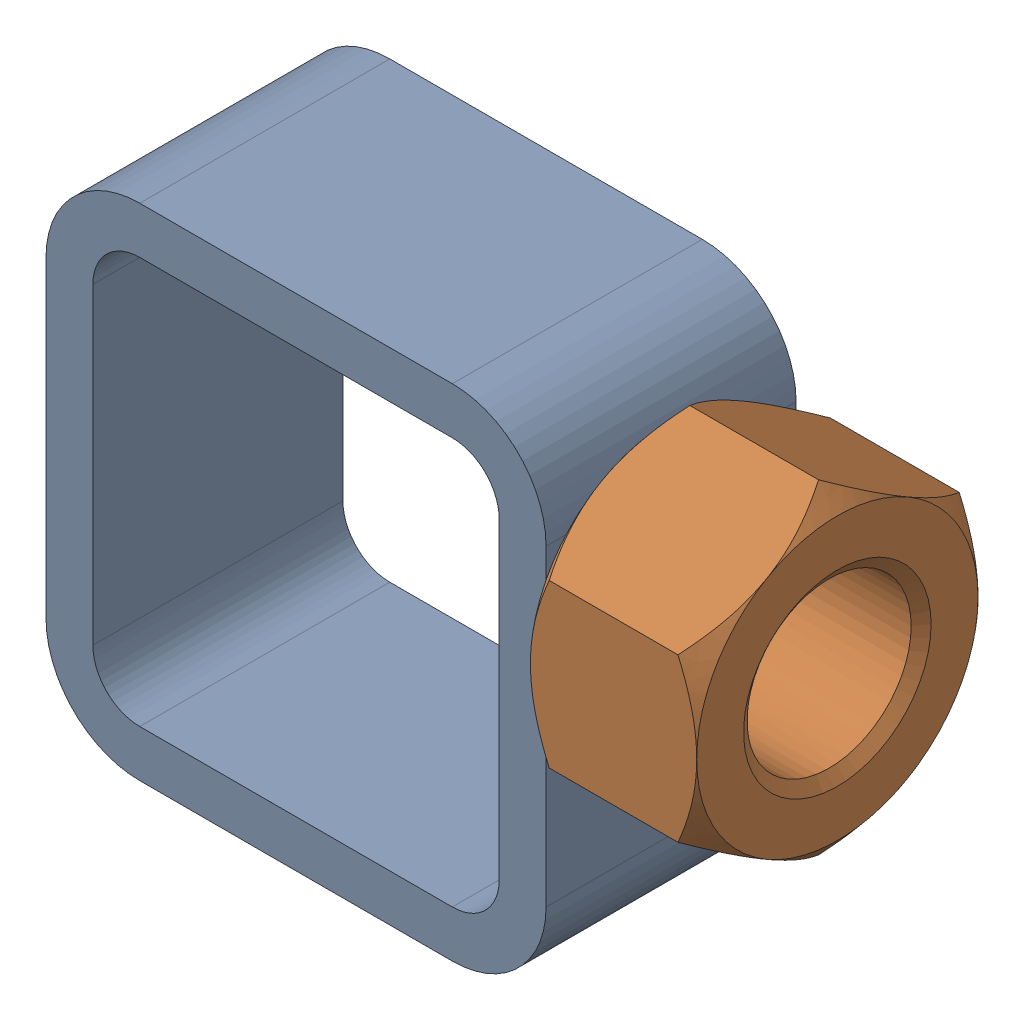
SolidWorks assembly 01-005-00-0, configuration Default. Lengths in mm.
Overall size (67.69 50.8 28.57).
2 component instances, 2 part files, 0 mates.
Components (placement in the parent):
- tube square_ai(PreviewCfg)-1: tube square_ai(PreviewCfg) [Default] at origin size (50.8 50.8 25.4)
- hex nut_ai(HNUT 0.7500-10-D-C)-1: hex nut_ai(HNUT 0.7500-10-D-C) [Default] at (67.691 31.75 0) x (0 0 -1) z (1 0 0) size (28.57 33 16.89)
